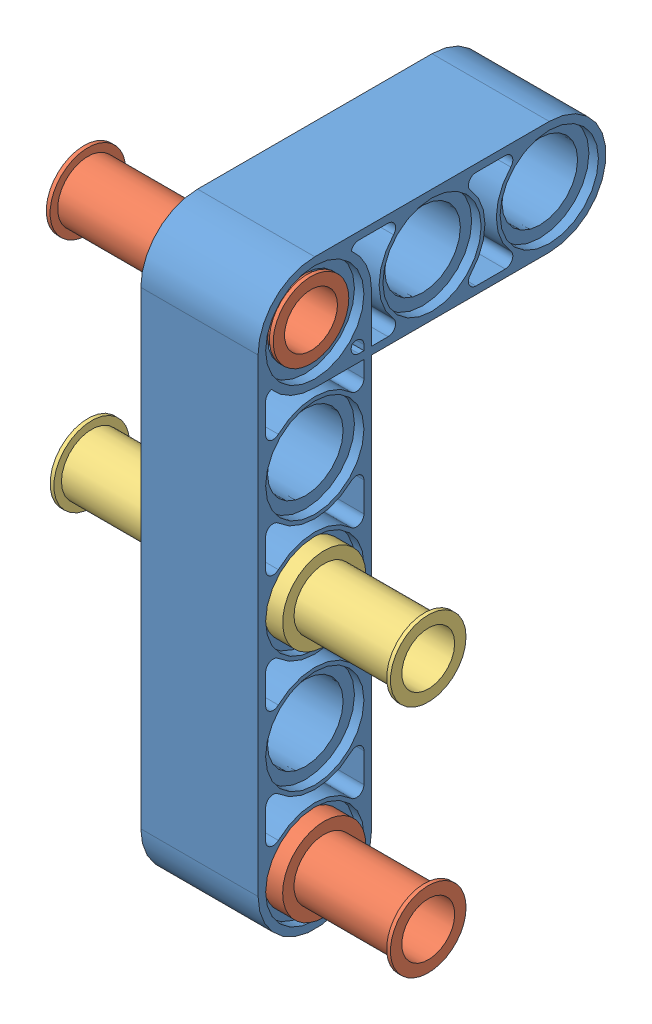
SolidWorks assembly right_connector, configuration Default. Lengths in mm.
Overall size (23.11 39.12 23.37).
4 component instances, 3 part files, 12 mates.
Components (placement in the parent):
- L_Three_Five_90degrees-1: L_Three_Five_90degrees [Default] x (0 1 0) z (-1 0 0) size (39.12 23.37 7.87)
- BlackConnectorSmall-1: BlackConnectorSmall [Default] at (0 7.874 0) x (-1 0 0) z (0 0 -1) size (15.24 5.59 5.59)
- BlackConnectorSmall-2: BlackConnectorSmall [Default] at (7.874 -23.622 0) x (-1 0 0) z (0 0 -1) size (15.24 5.59 5.59)
- BlueConnectorLong-1: BlueConnectorLong [Default] at (7.874 -7.874 0) x (-1 0 0) z (0 0 -1) size (22.86 5.59 5.59)
Mates (geometry in assembly coordinates):
- Coincident1: coincident aligned: plane of L_Three_Five_90degrees-1; plane of assembly through (0 0 0) normal (0 1 0)
- Coincident2: coincident anti-aligned: plane of L_Three_Five_90degrees-1; plane of assembly through (0 0 0) normal (0 0 1)
- Coincident3: coincident anti-aligned: plane of L_Three_Five_90degrees-1 through (0 0 0) normal (-1 0 0); plane of assembly through (0 0 0) normal (1 0 0)
- Concentric1: concentric aligned: cylinder of L_Three_Five_90degrees-1 through (-3.81 7.874 0) axis (1 0 0) radius 2.54; cylinder of BlackConnectorSmall-1 through (-4.4131 7.874 0) axis (1 0 0) radius 2.032
- Parallel1: parallel aligned: plane of BlackConnectorSmall-1; plane of assembly through (0 0 0) normal (0 1 0)
- Concentric2: concentric aligned: cylinder of L_Three_Five_90degrees-1 through (-3.81 -23.622 0) axis (1 0 0) radius 2.54; cylinder of BlackConnectorSmall-2 through (7.874 -23.622 0) axis (1 0 0) radius 2.032
- Parallel2: parallel aligned: plane of BlackConnectorSmall-2; plane of assembly through (0 0 0) normal (0 1 0)
- Concentric3: concentric aligned: cylinder of L_Three_Five_90degrees-1 through (-3.81 -7.874 0) axis (1 0 0) radius 2.54; cylinder of BlueConnectorLong-1 through (7.874 -7.874 0) axis (1 0 0) radius 2.032
- Coincident8: coincident anti-aligned: plane of L_Three_Five_90degrees-1 through (-0.381 -7.874 0) normal (1 0 0); plane of BlueConnectorLong-1 through (-0.381 -5.842 0) normal (-1 0 0)
- Parallel3: parallel aligned: plane of BlueConnectorLong-1; plane of assembly
- Coincident9: coincident anti-aligned: plane of L_Three_Five_90degrees-1 through (-0.381 -23.622 0) normal (1 0 0); plane of BlackConnectorSmall-2 through (-0.381 -21.59 0) normal (-1 0 0)
- Coincident10: coincident anti-aligned: plane of L_Three_Five_90degrees-1 through (-6.985 7.874 0) normal (-1 0 0); plane of BlackConnectorSmall-1 through (-6.985 10.668 0) normal (1 0 0)
